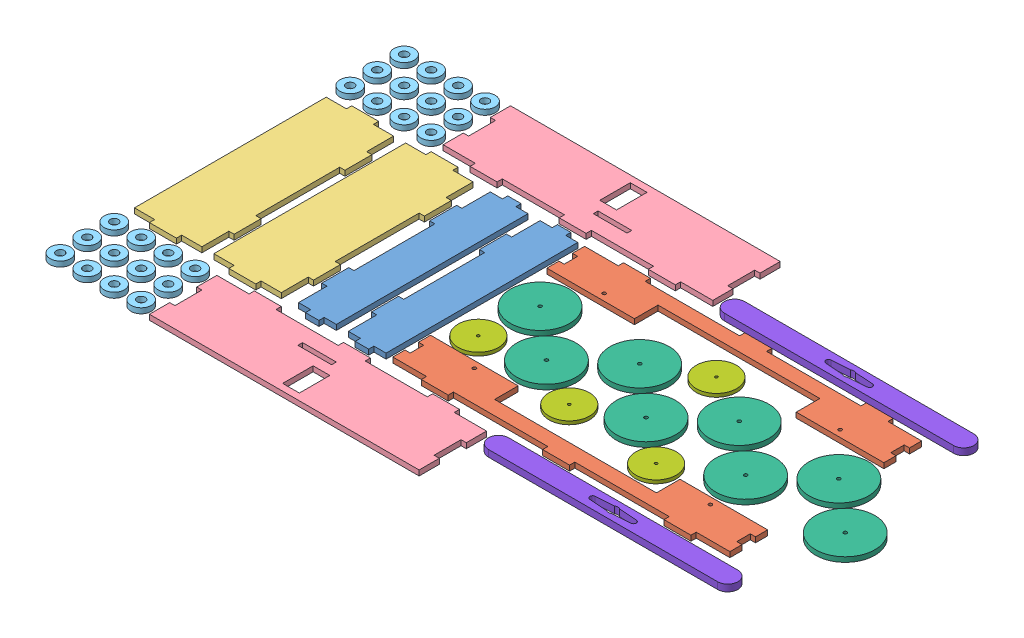
SolidWorks assembly Plastic Parts, configuration Default. Lengths in mm.
Overall size (510.29 5 275.55).
46 component instances, 8 part files, 135 mates.
Components (placement in the parent):
- Baseplate Short Side-1: Baseplate Short Side [Default] at (-426.9492 227.6568 258.8774) x (0 0 -1) z (1 0 0) size (150 3.9 31.9)
- Baseplate Wide Side-1: Baseplate Wide Side [Default] at (-246.0492 227.6568 201.7774) size (250 3.9 31.9)
- Chassis Short Side-1: Chassis Short Side [Default] at (-478.7492 227.6568 258.8774) x (0 0 -1) z (1 0 0) size (150 3.9 53.9)
- Chassis Wide Side-1: Chassis Wide Side [Default] at (-388.7492 227.6568 367.7774) size (200 3.9 53.9)
- Chassis Short Side-2: Chassis Short Side [Default] at (-537.6492 227.6568 258.8774) x (0 0 -1) z (1 0 0) size (150 3.9 53.9)
- Chassis Wide Side-2: Chassis Wide Side [Default] at (-388.7492 227.6568 149.9774) x (-1 0 0) z (0 0 -1) size (200 3.9 53.9)
- Baseplate Wide Side-2: Baseplate Wide Side [Default] at (-246.0492 227.6568 315.9774) x (-1 0 0) z (0 0 -1) size (250 3.9 31.9)
- Baseplate Short Side-2: Baseplate Short Side [Default] at (-390.0492 227.6568 258.8774) x (0 0 -1) z (1 0 0) size (150 3.9 31.9)
- Lift Axle-41: Lift Axle [Just the End] at (-561.2492 231.5568 346.3774) x (-0.413278 0 0.910605) z (0 -1 0) size (15 15 3.9)
- Lift Axle-42: Lift Axle [Just the End] at (-561.2492 231.5568 366.3774) x (-0.837224 0 -0.54686) z (0 -1 0) size (15 15 3.9)
- Lift Axle-43: Lift Axle [Just the End] at (-541.2492 231.5568 366.3774) x (-0.923391 0 -0.383861) z (0 -1 0) size (15 15 3.9)
- Lift Axle-44: Lift Axle [Just the End] at (-541.2492 231.5568 346.3774) x (0.712983 0 -0.701181) z (0 -1 0) size (15 15 3.9)
- Lift Axle-45: Lift Axle [Just the End] at (-521.2492 231.5568 346.3774) x (-0.688929 0 0.724829) z (0 -1 0) size (15 15 3.9)
- Lift Axle-46: Lift Axle [Just the End] at (-501.2492 231.5568 346.3774) x (-0.846423 0 -0.532511) z (0 -1 0) size (15 15 3.9)
- Lift Axle-47: Lift Axle [Just the End] at (-521.2492 231.5568 366.3774) x (-0.83717 0 -0.546942) z (0 -1 0) size (15 15 3.9)
- Lift Axle-48: Lift Axle [Just the End] at (-501.2492 231.5568 366.3774) x (-0.837169 0 -0.546945) z (0 -1 0) size (15 15 3.9)
- Wheel-1: Wheel [Just the End] at (-312.1147 285.9568 274.9774) x (0 1 0) z (0.574634 0 -0.818411) size (3.6 44 44)
- Wheel-2: Wheel [Just the End] at (-164.3766 285.9568 274.9774) x (0 1 0) z (0.049423 0 0.998778) size (3.6 44 44)
- Wheel-3: Wheel [Just the End] at (-90.5075 285.9568 274.9774) x (0 1 0) z (0.909173 0 -0.416419) size (3.6 44 44)
- Wheel-4: Wheel [Just the End] at (-238.2456 285.9568 274.9774) x (0 1 0) z (0.210384 0 0.977619) size (3.6 44 44)
- Pulley-1: Pulley [Just the End] at (-238.2456 241.5568 222.7814) x (0 1 0) z (-0.546944 0 0.837169) size (2.5 30 30)
- Pulley-3: Pulley [Just the End] at (-352.9996 241.5568 284.5912) x (0 1 0) z (0.807904 0 0.589315) size (2.5 30 30)
- Balance-1: Balance [Servo] at (-191.2492 226.5568 171.3774) size (185 5 15)
- Balance-2: Balance [Servo] at (-191.2492 226.5568 346.3774) size (185 5 15)
- Wheel-5: Wheel [Just the End] at (-201.3111 285.9568 242.7774) x (0 1 0) z (0.153769 0 0.988107) size (3.6 44 44)
- Wheel-6: Wheel [Just the End] at (-275.1802 285.9568 242.7774) x (0 1 0) z (0.291849 0 0.956464) size (3.6 44 44)
- Wheel-7: Wheel [Just the End] at (-127.442 285.9568 242.7774) x (0 1 0) z (-0.72689 0 0.686754) size (3.6 44 44)
- Wheel-8: Wheel [Just the End] at (-349.0492 285.9568 242.7774) x (0 1 0) z (-0.941015 0 0.338365) size (3.6 44 44)
- Lift Axle-57: Lift Axle [Just the End] at (-561.2492 231.5568 386.3774) x (0.928801 0 0.370578) z (0 -1 0) size (15 15 3.9)
- Lift Axle-58: Lift Axle [Just the End] at (-521.2492 231.5568 386.3774) x (-0.835695 0 -0.549193) z (0 -1 0) size (15 15 3.9)
- Lift Axle-59: Lift Axle [Just the End] at (-501.2492 231.5568 386.3774) x (0.447514 0 -0.894277) z (0 -1 0) size (15 15 3.9)
- Lift Axle-60: Lift Axle [Just the End] at (-541.2492 231.5568 386.3774) x (-0.998692 0 -0.051123) z (0 -1 0) size (15 15 3.9)
- Pulley-5: Pulley [Just the End] at (-205.0492 241.5568 300.7068) x (0 1 0) z (-0.924047 0 -0.382279) size (2.5 30 30)
- Pulley-6: Pulley [Just the End] at (-275.1802 241.5568 294.9734) x (0 1 0) z (0.752429 0 -0.658674) size (2.5 30 30)
- Lift Axle-66: Lift Axle [Just the End] at (-521.2492 231.5568 171.3774) x (-0.999114 0 -0.042077) z (0 -1 0) size (15 15 3.9)
- Lift Axle-67: Lift Axle [Just the End] at (-561.2492 231.5568 171.3774) x (0.447514 0 -0.894277) z (0 -1 0) size (15 15 3.9)
- Lift Axle-68: Lift Axle [Just the End] at (-541.2492 231.5568 171.3774) x (-0.879242 0 -0.476376) z (0 -1 0) size (15 15 3.9)
- Lift Axle-69: Lift Axle [Just the End] at (-501.2492 231.5568 171.3774) x (0.91604 0 0.401086) z (0 -1 0) size (15 15 3.9)
- Lift Axle-70: Lift Axle [Just the End] at (-521.2492 231.5568 151.3774) x (-0.879242 0 -0.476376) z (0 -1 0) size (15 15 3.9)
- Lift Axle-71: Lift Axle [Just the End] at (-541.2492 231.5568 151.3774) x (-0.998932 0 -0.046213) z (0 -1 0) size (15 15 3.9)
- Lift Axle-72: Lift Axle [Just the End] at (-501.2492 231.5568 151.3774) x (0.448674 0 -0.893696) z (0 -1 0) size (15 15 3.9)
- Lift Axle-73: Lift Axle [Just the End] at (-561.2492 231.5568 151.3774) x (0.91604 0 0.401086) z (0 -1 0) size (15 15 3.9)
- Lift Axle-74: Lift Axle [Just the End] at (-541.2492 231.5568 131.3774) x (-0.879242 0 -0.476376) z (0 -1 0) size (15 15 3.9)
- Lift Axle-75: Lift Axle [Just the End] at (-521.2492 231.5568 131.3774) x (-0.999822 0 -0.018854) z (0 -1 0) size (15 15 3.9)
- Lift Axle-76: Lift Axle [Just the End] at (-561.2492 231.5568 131.3774) x (0.447514 0 -0.894277) z (0 -1 0) size (15 15 3.9)
- Lift Axle-77: Lift Axle [Just the End] at (-501.2492 231.5568 131.3774) x (0.359916 0 0.932985) z (0 -1 0) size (15 15 3.9)
Mates (geometry in assembly coordinates):
- Coincident2: coincident aligned: plane of Baseplate Wide Side-1 through (-246.0492 231.5568 201.7774) normal (0 1 0); plane of Chassis Short Side-1 through (-478.7492 231.5568 258.8774) normal (0 1 0)
- Coincident3: coincident aligned: plane of Baseplate Wide Side-1 through (-246.0492 231.5568 201.7774) normal (0 1 0); plane of Chassis Wide Side-1 through (-388.7492 231.5568 367.7774) normal (0 1 0)
- Coincident5: coincident aligned: plane of Baseplate Short Side-1 through (-426.9492 231.5568 258.8774) normal (0 1 0); plane of Baseplate Wide Side-1 through (-246.0492 231.5568 201.7774) normal (0 1 0)
- Coincident17: coincident aligned: plane of Chassis Short Side-1 through (-478.7492 231.5568 258.8774) normal (0 1 0); plane of Chassis Short Side-2 through (-537.6492 231.5568 258.8774) normal (0 1 0)
- Coincident18: coincident aligned: plane of Chassis Short Side-1 through (-488.7492 231.5568 183.8774) normal (0 0 -1); plane of Chassis Short Side-2 through (-547.6492 231.5568 183.8774) normal (0 0 -1)
- Distance7: distance = 5 mm anti-aligned: plane of Chassis Short Side-2 through (-508.7492 231.5568 227.7774) normal (1 0 0); plane of Chassis Short Side-1 through (-503.7492 231.5568 329.9774) normal (-1 0 0)
- Distance11: distance = 5 mm anti-aligned: plane of Baseplate Short Side-1 through (-412.9492 231.5568 329.9774) normal (1 0 0); plane of Baseplate Short Side-2 through (-407.9492 231.5568 208.8774) normal (-1 0 0)
- Coincident33: coincident aligned: plane of Baseplate Short Side-1 through (-426.9492 231.5568 258.8774) normal (0 1 0); plane of Baseplate Short Side-2 through (-390.0492 231.5568 258.8774) normal (0 1 0)
- Coincident34: coincident aligned: plane of Baseplate Short Side-1 through (-431.9492 231.5568 183.8774) normal (0 0 -1); plane of Baseplate Short Side-2 through (-395.0492 231.5568 183.8774) normal (0 0 -1)
- Coincident69: coincident aligned: plane of Lift Axle-45 through (-521.2492 231.5568 346.3774) normal (0 1 0); plane of Lift Axle-48 through (-501.2492 231.5568 366.3774) normal (0 1 0)
- Coincident70: coincident aligned: plane of Lift Axle-45 through (-521.2492 231.5568 346.3774) normal (0 1 0); plane of Lift Axle-46 through (-501.2492 231.5568 346.3774) normal (0 1 0)
- Coincident71: coincident aligned: plane of Lift Axle-44 through (-541.2492 231.5568 346.3774) normal (0 1 0); plane of Lift Axle-45 through (-521.2492 231.5568 346.3774) normal (0 1 0)
- Coincident72: coincident aligned: plane of Lift Axle-42 through (-561.2492 231.5568 366.3774) normal (0 1 0); plane of Lift Axle-45 through (-521.2492 231.5568 346.3774) normal (0 1 0)
- Coincident73: coincident aligned: plane of Lift Axle-43 through (-541.2492 231.5568 366.3774) normal (0 1 0); plane of Lift Axle-45 through (-521.2492 231.5568 346.3774) normal (0 1 0)
- Coincident74: coincident aligned: plane of Lift Axle-45 through (-521.2492 231.5568 346.3774) normal (0 1 0); plane of Lift Axle-47 through (-521.2492 231.5568 366.3774) normal (0 1 0)
- Coincident75: coincident aligned: plane of Lift Axle-41 through (-561.2492 231.5568 346.3774) normal (0 1 0); plane of Lift Axle-45 through (-521.2492 231.5568 346.3774) normal (0 1 0)
- Distance87: distance = 5 mm: cylinder of Lift Axle-43 through (-541.2492 227.6568 366.3774) axis (0 1 0) radius 7.5; cylinder of Lift Axle-47 through (-521.2492 227.6568 366.3774) axis (0 1 0) radius 7.5
- Distance88: distance = 5 mm: cylinder of Lift Axle-47 through (-521.2492 227.6568 366.3774) axis (0 1 0) radius 7.5; cylinder of Lift Axle-48 through (-501.2492 227.6568 366.3774) axis (0 1 0) radius 7.5
- Distance89: distance = 5 mm: cylinder of Lift Axle-46 through (-501.2492 227.6568 346.3774) axis (0 1 0) radius 7.5; cylinder of Lift Axle-48 through (-501.2492 227.6568 366.3774) axis (0 1 0) radius 7.5
- Distance90: distance = 5 mm: cylinder of Lift Axle-44 through (-541.2492 227.6568 346.3774) axis (0 1 0) radius 7.5; cylinder of Lift Axle-41 through (-561.2492 227.6568 346.3774) axis (0 1 0) radius 7.5
- Distance91: distance = 5 mm: cylinder of Lift Axle-45 through (-521.2492 227.6568 346.3774) axis (0 1 0) radius 7.5; cylinder of Lift Axle-44 through (-541.2492 227.6568 346.3774) axis (0 1 0) radius 7.5
- Distance92: distance = 5 mm: cylinder of Lift Axle-42 through (-561.2492 227.6568 366.3774) axis (0 1 0) radius 7.5; cylinder of Lift Axle-43 through (-541.2492 227.6568 366.3774) axis (0 1 0) radius 7.5
- Distance93: distance = 5 mm: cylinder of Lift Axle-45 through (-521.2492 227.6568 346.3774) axis (0 1 0) radius 7.5; cylinder of Lift Axle-47 through (-521.2492 227.6568 366.3774) axis (0 1 0) radius 7.5
- Distance94: distance = 5 mm: cylinder of Lift Axle-44 through (-541.2492 227.6568 346.3774) axis (0 1 0) radius 7.5; cylinder of Lift Axle-43 through (-541.2492 227.6568 366.3774) axis (0 1 0) radius 7.5
- Distance95: distance = 5 mm: cylinder of Lift Axle-41 through (-561.2492 227.6568 346.3774) axis (0 1 0) radius 7.5; cylinder of Lift Axle-42 through (-561.2492 227.6568 366.3774) axis (0 1 0) radius 7.5
- Distance96: distance = 5 mm: cylinder of Lift Axle-46 through (-501.2492 227.6568 346.3774) axis (0 1 0) radius 7.5; cylinder of Lift Axle-45 through (-521.2492 227.6568 346.3774) axis (0 1 0) radius 7.5
- Coincident76: coincident aligned: plane of Chassis Wide Side-1 through (-388.7492 231.5568 367.7774) normal (0 1 0); plane of Lift Axle-46 through (-501.2492 231.5568 346.3774) normal (0 1 0)
- Distance97: distance = 5 mm anti-aligned: cylinder of Lift Axle-46 through (-501.2492 227.6568 346.3774) axis (0 1 0) radius 7.5; plane of Chassis Short Side-1 through (-488.7492 231.5568 333.8774) normal (0 0 1)
- Distance98: distance = 5 mm anti-aligned: cylinder of Lift Axle-46 through (-501.2492 227.6568 346.3774) axis (0 1 0) radius 7.5; plane of Chassis Wide Side-1 through (-488.7492 231.5568 367.7774) normal (-1 0 0)
- Distance99: distance = 5 mm anti-aligned: cylinder of Lift Axle-48 through (-501.2492 227.6568 366.3774) axis (0 1 0) radius 7.5; plane of Chassis Wide Side-1 through (-488.7492 231.5568 367.7774) normal (-1 0 0)
- Distance100: distance = 5 mm anti-aligned: cylinder of Lift Axle-45 through (-521.2492 227.6568 346.3774) axis (0 1 0) radius 7.5; plane of Chassis Short Side-1 through (-488.7492 231.5568 333.8774) normal (0 0 1)
- Distance101: distance = 5 mm anti-aligned: cylinder of Lift Axle-44 through (-541.2492 227.6568 346.3774) axis (0 1 0) radius 7.5; plane of Chassis Short Side-1 through (-488.7492 231.5568 333.8774) normal (0 0 1)
- Distance102: distance = 5 mm anti-aligned: cylinder of Lift Axle-41 through (-561.2492 227.6568 346.3774) axis (0 1 0) radius 7.5; plane of Chassis Short Side-2 through (-547.6492 231.5568 333.8774) normal (0 0 1)
- Coincident86: coincident aligned: plane of Wheel-3 through (-90.5075 231.5568 274.9774) normal (0 1 0); plane of Wheel-4 through (-238.2456 231.5568 274.9774) normal (0 1 0)
- Coincident87: coincident aligned: plane of Wheel-2 through (-164.3766 231.5568 274.9774) normal (0 1 0); plane of Wheel-4 through (-238.2456 231.5568 274.9774) normal (0 1 0)
- Coincident88: coincident aligned: plane of Wheel-1 through (-312.1147 231.5568 274.9774) normal (0 1 0); plane of Wheel-4 through (-238.2456 231.5568 274.9774) normal (0 1 0)
- Coincident89: coincident aligned: plane of Baseplate Wide Side-2 through (-246.0492 231.5568 315.9774) normal (0 1 0); plane of Wheel-4 through (-238.2456 231.5568 274.9774) normal (0 1 0)
- Distance124: distance = 5 mm anti-aligned: cylinder of Wheel-3 through (-90.5075 285.9568 274.9774) axis (0 1 0) radius 22; plane of Baseplate Wide Side-2 through (-246.0492 231.5568 301.9774) normal (0 0 -1)
- Distance126: distance = 5 mm anti-aligned: cylinder of Wheel-4 through (-238.2456 285.9568 274.9774) axis (0 1 0) radius 22; plane of Baseplate Wide Side-2 through (-246.0492 231.5568 301.9774) normal (0 0 -1)
- Distance128: distance = 5 mm anti-aligned: cylinder of Wheel-2 through (-164.3766 285.9568 274.9774) axis (0 1 0) radius 22; plane of Baseplate Wide Side-2 through (-246.0492 231.5568 301.9774) normal (0 0 -1)
- Coincident100: coincident aligned: plane of Baseplate Wide Side-2 through (-246.0492 231.5568 315.9774) normal (0 1 0); plane of Pulley-1 through (-238.2456 231.5568 222.7814) normal (0 1 0)
- Coincident101: coincident aligned: plane of Baseplate Short Side-2 through (-390.0492 231.5568 258.8774) normal (0 1 0); plane of Pulley-3 through (-352.9996 231.5568 284.5912) normal (0 1 0)
- Coincident102: coincident: plane of Chassis Wide Side-1 through (-388.7492 231.5568 367.7774) normal (0 1 0); plane of Balance-2 through (-196.6235 231.5568 346.3774) normal (0 1 0)
- Coincident103: coincident aligned: plane of Wheel-5 through (-201.3111 231.5568 242.7774) normal (0 1 0); plane of Wheel-7 through (-127.442 231.5568 242.7774) normal (0 1 0)
- Coincident104: coincident aligned: plane of Wheel-5 through (-201.3111 231.5568 242.7774) normal (0 1 0); plane of Wheel-8 through (-349.0492 231.5568 242.7774) normal (0 1 0)
- Coincident105: coincident aligned: plane of Wheel-5 through (-201.3111 231.5568 242.7774) normal (0 1 0); plane of Wheel-6 through (-275.1802 231.5568 242.7774) normal (0 1 0)
- Distance142: distance = 5 mm anti-aligned: cylinder of Wheel-7 through (-127.442 285.9568 242.7774) axis (0 1 0) radius 22; plane of Baseplate Wide Side-1 through (-246.0492 231.5568 215.7774) normal (0 0 1)
- Distance143: distance = 5 mm anti-aligned: cylinder of Wheel-5 through (-201.3111 285.9568 242.7774) axis (0 1 0) radius 22; plane of Baseplate Wide Side-1 through (-246.0492 231.5568 215.7774) normal (0 0 1)
- Distance144: distance = 5 mm anti-aligned: cylinder of Wheel-6 through (-275.1802 285.9568 242.7774) axis (0 1 0) radius 22; plane of Baseplate Wide Side-1 through (-246.0492 231.5568 215.7774) normal (0 0 1)
- Distance145: distance = 5 mm anti-aligned: cylinder of Wheel-8 through (-349.0492 285.9568 242.7774) axis (0 1 0) radius 22; plane of Baseplate Wide Side-1 through (-246.0492 231.5568 215.7774) normal (0 0 1)
- Distance147: distance = 5 mm: cylinder of Lift Axle-60 through (-541.2492 227.6568 386.3774) axis (0 1 0) radius 7.5; cylinder of Lift Axle-58 through (-521.2492 227.6568 386.3774) axis (0 1 0) radius 7.5
- Distance148: distance = 5 mm: cylinder of Lift Axle-57 through (-561.2492 227.6568 386.3774) axis (0 1 0) radius 7.5; cylinder of Lift Axle-60 through (-541.2492 227.6568 386.3774) axis (0 1 0) radius 7.5
- Distance149: distance = 5 mm: cylinder of Lift Axle-58 through (-521.2492 227.6568 386.3774) axis (0 1 0) radius 7.5; cylinder of Lift Axle-59 through (-501.2492 227.6568 386.3774) axis (0 1 0) radius 7.5
- Distance150: distance = 5 mm: cylinder of Lift Axle-59 through (-501.2492 227.6568 386.3774) axis (0 1 0) radius 7.5; cylinder of Lift Axle-48 through (-501.2492 227.6568 366.3774) axis (0 1 0) radius 7.5
- Coincident113: coincident aligned: plane of Chassis Wide Side-1 through (-388.7492 231.5568 367.7774) normal (0 1 0); plane of Lift Axle-59 through (-501.2492 231.5568 386.3774) normal (0 1 0)
- Coincident114: coincident aligned: plane of Chassis Wide Side-1 through (-388.7492 231.5568 367.7774) normal (0 1 0); plane of Lift Axle-58 through (-521.2492 231.5568 386.3774) normal (0 1 0)
- Coincident115: coincident aligned: plane of Chassis Short Side-2 through (-537.6492 231.5568 258.8774) normal (0 1 0); plane of Lift Axle-57 through (-561.2492 231.5568 386.3774) normal (0 1 0)
- Coincident116: coincident aligned: plane of Chassis Short Side-1 through (-478.7492 231.5568 258.8774) normal (0 1 0); plane of Lift Axle-60 through (-541.2492 231.5568 386.3774) normal (0 1 0)
- Distance151: distance = 5 mm anti-aligned: cylinder of Lift Axle-59 through (-501.2492 227.6568 386.3774) axis (0 1 0) radius 7.5; plane of Chassis Wide Side-1 through (-488.7492 231.5568 367.7774) normal (-1 0 0)
- Distance153: distance = 5 mm: cylinder of Lift Axle-58 through (-521.2492 227.6568 386.3774) axis (0 1 0) radius 7.5; cylinder of Lift Axle-47 through (-521.2492 227.6568 366.3774) axis (0 1 0) radius 7.5
- Distance154: distance = 5 mm: cylinder of Lift Axle-60 through (-541.2492 227.6568 386.3774) axis (0 1 0) radius 7.5; cylinder of Lift Axle-43 through (-541.2492 227.6568 366.3774) axis (0 1 0) radius 7.5
- Distance156: distance = 5 mm: cylinder of Lift Axle-57 through (-561.2492 227.6568 386.3774) axis (0 1 0) radius 7.5; cylinder of Lift Axle-42 through (-561.2492 227.6568 366.3774) axis (0 1 0) radius 7.5
- Coincident128: coincident aligned: plane of Baseplate Short Side-1 through (-426.9492 231.5568 258.8774) normal (0 1 0); plane of Pulley-6 through (-275.1802 231.5568 294.9734) normal (0 1 0)
- Coincident129: coincident aligned: plane of Baseplate Short Side-2 through (-390.0492 231.5568 258.8774) normal (0 1 0); plane of Pulley-5 through (-205.0492 231.5568 300.7068) normal (0 1 0)
- Distance172: distance = 5 mm anti-aligned: plane of Baseplate Short Side-1 through (-444.8492 231.5568 208.8774) normal (-1 0 0); plane of Chassis Short Side-1 through (-449.8492 231.5568 227.7774) normal (1 0 0)
- Distance173: distance = 5 mm anti-aligned: plane of Baseplate Short Side-2 through (-395.0492 231.5568 333.8774) normal (0 0 1); plane of Chassis Wide Side-1 through (-388.7492 231.5568 338.8774) normal (0 0 -1)
- Coincident134: coincident aligned: plane of Chassis Wide Side-2 through (-388.7492 231.5568 149.9774) normal (0 1 0); plane of Baseplate Short Side-2 through (-390.0492 231.5568 258.8774) normal (0 1 0)
- Coincident135: coincident aligned: plane of Chassis Wide Side-1 through (-388.7492 231.5568 367.7774) normal (0 1 0); plane of Baseplate Wide Side-2 through (-246.0492 231.5568 315.9774) normal (0 1 0)
- Distance174: distance = 5 mm anti-aligned: plane of Baseplate Wide Side-2 through (-371.0492 231.5568 315.9774) normal (-1 0 0); plane of Baseplate Short Side-2 through (-376.0492 231.5568 329.9774) normal (1 0 0)
- Distance176: distance = 5 mm anti-aligned: plane of Chassis Wide Side-1 through (-388.7492 231.5568 338.8774) normal (0 0 -1); plane of Baseplate Wide Side-2 through (-246.0492 231.5568 333.8774) normal (0 0 1)
- Distance177: distance = 5 mm anti-aligned: plane of Baseplate Short Side-2 through (-395.0492 231.5568 183.8774) normal (0 0 -1); plane of Chassis Wide Side-2 through (-388.7492 231.5568 178.8774) normal (0 0 1)
- Coincident146: coincident aligned: plane of Chassis Short Side-1 through (-488.7492 231.5568 187.7774) normal (-1 0 0); plane of Chassis Wide Side-2 through (-488.7492 231.5568 149.9774) normal (-1 0 0)
- Coincident147: coincident aligned: plane of Chassis Short Side-1 through (-488.7492 231.5568 329.9774) normal (-1 0 0); plane of Chassis Wide Side-1 through (-488.7492 231.5568 367.7774) normal (-1 0 0)
- Distance178: distance = 5 mm anti-aligned: plane of Chassis Short Side-1 through (-488.7492 231.5568 183.8774) normal (0 0 -1); plane of Chassis Wide Side-2 through (-388.7492 231.5568 178.8774) normal (0 0 1)
- Coincident149: coincident aligned: plane of Chassis Wide Side-2 through (-388.7492 231.5568 149.9774) normal (0 1 0); plane of Balance-1 through (-191.2492 231.5568 171.3774) normal (0 1 0)
- Coincident152: coincident aligned: plane of Chassis Wide Side-2 through (-388.7492 231.5568 149.9774) normal (0 1 0); plane of Wheel-8 through (-349.0492 231.5568 242.7774) normal (0 1 0)
- Distance185: distance = 5 mm anti-aligned: plane of Baseplate Wide Side-1 through (-246.0492 231.5568 183.8774) normal (0 0 -1); plane of Chassis Wide Side-2 through (-388.7492 231.5568 178.8774) normal (0 0 1)
- Distance186: distance = 5 mm anti-aligned: plane of Baseplate Short Side-2 through (-376.0492 231.5568 329.9774) normal (1 0 0); plane of Baseplate Wide Side-1 through (-371.0492 231.5568 201.7774) normal (-1 0 0)
- Distance187: distance = 5 mm anti-aligned: cylinder of Wheel-1 through (-312.1147 285.9568 274.9774) axis (0 1 0) radius 22; plane of Baseplate Wide Side-2 through (-246.0492 231.5568 301.9774) normal (0 0 -1)
- Distance188: distance = 5 mm: cylinder of Wheel-1 through (-312.1147 285.9568 274.9774) axis (0 1 0) radius 22; cylinder of Wheel-8 through (-349.0492 285.9568 242.7774) axis (0 1 0) radius 22
- Distance189: distance = 5 mm anti-aligned: plane of Baseplate Short Side-2 through (-376.0492 231.5568 329.9774) normal (1 0 0); cylinder of Wheel-8 through (-349.0492 285.9568 242.7774) axis (0 1 0) radius 22
- Distance190: distance = 5 mm: cylinder of Wheel-6 through (-275.1802 285.9568 242.7774) axis (0 1 0) radius 22; cylinder of Wheel-1 through (-312.1147 285.9568 274.9774) axis (0 1 0) radius 22
- Distance191: distance = 5 mm: cylinder of Wheel-4 through (-238.2456 285.9568 274.9774) axis (0 1 0) radius 22; cylinder of Wheel-6 through (-275.1802 285.9568 242.7774) axis (0 1 0) radius 22
- Distance192: distance = 5 mm: cylinder of Wheel-5 through (-201.3111 285.9568 242.7774) axis (0 1 0) radius 22; cylinder of Wheel-4 through (-238.2456 285.9568 274.9774) axis (0 1 0) radius 22
- Distance193: distance = 5 mm: cylinder of Wheel-2 through (-164.3766 285.9568 274.9774) axis (0 1 0) radius 22; cylinder of Wheel-5 through (-201.3111 285.9568 242.7774) axis (0 1 0) radius 22
- Distance194: distance = 5 mm: cylinder of Wheel-7 through (-127.442 285.9568 242.7774) axis (0 1 0) radius 22; cylinder of Wheel-2 through (-164.3766 285.9568 274.9774) axis (0 1 0) radius 22
- Distance195: distance = 5 mm: cylinder of Wheel-3 through (-90.5075 285.9568 274.9774) axis (0 1 0) radius 22; cylinder of Wheel-7 through (-127.442 285.9568 242.7774) axis (0 1 0) radius 22
- Distance196: distance = 5 mm: cylinder of Wheel-4 through (-238.2456 285.9568 274.9774) axis (0 1 0) radius 22; cylinder of Pulley-6 through (-275.1802 229.0568 294.9734) axis (0 -1 0) radius 15
- Distance197: distance = 5 mm: cylinder of Pulley-6 through (-275.1802 229.0568 294.9734) axis (0 -1 0) radius 15; cylinder of Wheel-1 through (-312.1147 285.9568 274.9774) axis (0 1 0) radius 22
- Distance199: distance = 5 mm: cylinder of Wheel-4 through (-238.2456 285.9568 274.9774) axis (0 1 0) radius 22; cylinder of Pulley-5 through (-205.0492 229.0568 300.7068) axis (0 -1 0) radius 15
- Distance201: distance = 5 mm: cylinder of Wheel-1 through (-312.1147 285.9568 274.9774) axis (0 1 0) radius 22; cylinder of Pulley-3 through (-352.9996 229.0568 284.5912) axis (0 -1 0) radius 15
- Distance202: distance = 5 mm: cylinder of Pulley-3 through (-352.9996 229.0568 284.5912) axis (0 -1 0) radius 15; cylinder of Wheel-8 through (-349.0492 285.9568 242.7774) axis (0 1 0) radius 22
- Distance203: distance = 5 mm: cylinder of Pulley-1 through (-238.2456 229.0568 222.7814) axis (0 -1 0) radius 15; cylinder of Wheel-5 through (-201.3111 285.9568 242.7774) axis (0 1 0) radius 22
- Distance204: distance = 5 mm: cylinder of Pulley-1 through (-238.2456 229.0568 222.7814) axis (0 -1 0) radius 15; cylinder of Wheel-6 through (-275.1802 285.9568 242.7774) axis (0 1 0) radius 22
- Distance205: distance = 4 mm anti-aligned: plane of Baseplate Wide Side-2 through (-186.0492 231.5568 315.9774) normal (-1 0 0); cylinder of Pulley-5 through (-205.0492 229.0568 300.7068) axis (0 -1 0) radius 15
- Distance206: distance = 5 mm: cylinder of Lift Axle-68 through (-541.2492 227.6568 171.3774) axis (0 1 0) radius 7.5; cylinder of Lift Axle-67 through (-561.2492 227.6568 171.3774) axis (0 1 0) radius 7.5
- Distance207: distance = 5 mm: cylinder of Lift Axle-66 through (-521.2492 227.6568 171.3774) axis (0 1 0) radius 7.5; cylinder of Lift Axle-68 through (-541.2492 227.6568 171.3774) axis (0 1 0) radius 7.5
- Distance208: distance = 5 mm: cylinder of Lift Axle-69 through (-501.2492 227.6568 171.3774) axis (0 1 0) radius 7.5; cylinder of Lift Axle-66 through (-521.2492 227.6568 171.3774) axis (0 1 0) radius 7.5
- Coincident157: coincident aligned: plane of Chassis Short Side-2 through (-537.6492 231.5568 258.8774) normal (0 1 0); plane of Lift Axle-67 through (-561.2492 231.5568 171.3774) normal (0 1 0)
- Coincident158: coincident aligned: plane of Chassis Short Side-2 through (-537.6492 231.5568 258.8774) normal (0 1 0); plane of Lift Axle-69 through (-501.2492 231.5568 171.3774) normal (0 1 0)
- Coincident159: coincident aligned: plane of Chassis Short Side-2 through (-537.6492 231.5568 258.8774) normal (0 1 0); plane of Lift Axle-68 through (-541.2492 231.5568 171.3774) normal (0 1 0)
- Coincident160: coincident aligned: plane of Chassis Short Side-2 through (-537.6492 231.5568 258.8774) normal (0 1 0); plane of Lift Axle-66 through (-521.2492 231.5568 171.3774) normal (0 1 0)
- Distance209: distance = 5 mm anti-aligned: cylinder of Lift Axle-69 through (-501.2492 227.6568 171.3774) axis (0 1 0) radius 7.5; plane of Chassis Short Side-2 through (-547.6492 231.5568 183.8774) normal (0 0 -1)
- Distance210: distance = 5 mm anti-aligned: cylinder of Lift Axle-66 through (-521.2492 227.6568 171.3774) axis (0 1 0) radius 7.5; plane of Chassis Short Side-2 through (-547.6492 231.5568 183.8774) normal (0 0 -1)
- Distance211: distance = 5 mm anti-aligned: cylinder of Lift Axle-68 through (-541.2492 227.6568 171.3774) axis (0 1 0) radius 7.5; plane of Chassis Short Side-2 through (-547.6492 231.5568 183.8774) normal (0 0 -1)
- Distance212: distance = 5 mm anti-aligned: cylinder of Lift Axle-67 through (-561.2492 227.6568 171.3774) axis (0 1 0) radius 7.5; plane of Chassis Short Side-2 through (-547.6492 231.5568 183.8774) normal (0 0 -1)
- Distance213: distance = 5 mm anti-aligned: cylinder of Lift Axle-69 through (-501.2492 227.6568 171.3774) axis (0 1 0) radius 7.5; plane of Chassis Wide Side-2 through (-488.7492 231.5568 149.9774) normal (-1 0 0)
- Distance214: distance = 5 mm: cylinder of Lift Axle-73 through (-561.2492 227.6568 151.3774) axis (0 1 0) radius 7.5; cylinder of Lift Axle-71 through (-541.2492 227.6568 151.3774) axis (0 1 0) radius 7.5
- Distance215: distance = 5 mm: cylinder of Lift Axle-71 through (-541.2492 227.6568 151.3774) axis (0 1 0) radius 7.5; cylinder of Lift Axle-70 through (-521.2492 227.6568 151.3774) axis (0 1 0) radius 7.5
- Distance216: distance = 5 mm: cylinder of Lift Axle-70 through (-521.2492 227.6568 151.3774) axis (0 1 0) radius 7.5; cylinder of Lift Axle-72 through (-501.2492 227.6568 151.3774) axis (0 1 0) radius 7.5
- Distance217: distance = 5 mm: cylinder of Lift Axle-77 through (-501.2492 227.6568 131.3774) axis (0 1 0) radius 7.5; cylinder of Lift Axle-75 through (-521.2492 227.6568 131.3774) axis (0 1 0) radius 7.5
- Distance218: distance = 5 mm: cylinder of Lift Axle-75 through (-521.2492 227.6568 131.3774) axis (0 1 0) radius 7.5; cylinder of Lift Axle-74 through (-541.2492 227.6568 131.3774) axis (0 1 0) radius 7.5
- Distance219: distance = 5 mm: cylinder of Lift Axle-74 through (-541.2492 227.6568 131.3774) axis (0 1 0) radius 7.5; cylinder of Lift Axle-76 through (-561.2492 227.6568 131.3774) axis (0 1 0) radius 7.5
- Coincident161: coincident aligned: plane of Chassis Wide Side-2 through (-388.7492 231.5568 149.9774) normal (0 1 0); plane of Lift Axle-73 through (-561.2492 231.5568 151.3774) normal (0 1 0)
- Coincident162: coincident aligned: plane of Chassis Wide Side-2 through (-388.7492 231.5568 149.9774) normal (0 1 0); plane of Lift Axle-71 through (-541.2492 231.5568 151.3774) normal (0 1 0)
- Coincident163: coincident aligned: plane of Chassis Wide Side-2 through (-388.7492 231.5568 149.9774) normal (0 1 0); plane of Lift Axle-70 through (-521.2492 231.5568 151.3774) normal (0 1 0)
- Coincident164: coincident aligned: plane of Chassis Wide Side-2 through (-388.7492 231.5568 149.9774) normal (0 1 0); plane of Lift Axle-72 through (-501.2492 231.5568 151.3774) normal (0 1 0)
- Coincident165: coincident aligned: plane of Chassis Wide Side-2 through (-388.7492 231.5568 149.9774) normal (0 1 0); plane of Lift Axle-76 through (-561.2492 231.5568 131.3774) normal (0 1 0)
- Coincident166: coincident aligned: plane of Chassis Wide Side-2 through (-388.7492 231.5568 149.9774) normal (0 1 0); plane of Lift Axle-74 through (-541.2492 231.5568 131.3774) normal (0 1 0)
- Coincident167: coincident aligned: plane of Chassis Wide Side-2 through (-388.7492 231.5568 149.9774) normal (0 1 0); plane of Lift Axle-75 through (-521.2492 231.5568 131.3774) normal (0 1 0)
- Coincident168: coincident aligned: plane of Chassis Wide Side-2 through (-388.7492 231.5568 149.9774) normal (0 1 0); plane of Lift Axle-77 through (-501.2492 231.5568 131.3774) normal (0 1 0)
- Distance220: distance = 5 mm anti-aligned: cylinder of Lift Axle-72 through (-501.2492 227.6568 151.3774) axis (0 1 0) radius 7.5; plane of Chassis Wide Side-2 through (-488.7492 231.5568 149.9774) normal (-1 0 0)
- Distance221: distance = 5 mm anti-aligned: cylinder of Lift Axle-77 through (-501.2492 227.6568 131.3774) axis (0 1 0) radius 7.5; plane of Chassis Wide Side-2 through (-488.7492 231.5568 149.9774) normal (-1 0 0)
- Distance223: distance = 5 mm: cylinder of Lift Axle-72 through (-501.2492 227.6568 151.3774) axis (0 1 0) radius 7.5; cylinder of Lift Axle-69 through (-501.2492 227.6568 171.3774) axis (0 1 0) radius 7.5
- Distance224: distance = 5 mm: cylinder of Lift Axle-70 through (-521.2492 227.6568 151.3774) axis (0 1 0) radius 7.5; cylinder of Lift Axle-66 through (-521.2492 227.6568 171.3774) axis (0 1 0) radius 7.5
- Distance225: distance = 5 mm: cylinder of Lift Axle-71 through (-541.2492 227.6568 151.3774) axis (0 1 0) radius 7.5; cylinder of Lift Axle-68 through (-541.2492 227.6568 171.3774) axis (0 1 0) radius 7.5
- Distance226: distance = 5 mm: cylinder of Lift Axle-73 through (-561.2492 227.6568 151.3774) axis (0 1 0) radius 7.5; cylinder of Lift Axle-67 through (-561.2492 227.6568 171.3774) axis (0 1 0) radius 7.5
- Distance227: distance = 5 mm: cylinder of Lift Axle-77 through (-501.2492 227.6568 131.3774) axis (0 1 0) radius 7.5; cylinder of Lift Axle-72 through (-501.2492 227.6568 151.3774) axis (0 1 0) radius 7.5
- Distance228: distance = 5 mm: cylinder of Lift Axle-75 through (-521.2492 227.6568 131.3774) axis (0 1 0) radius 7.5; cylinder of Lift Axle-70 through (-521.2492 227.6568 151.3774) axis (0 1 0) radius 7.5
- Distance229: distance = 5 mm: cylinder of Lift Axle-74 through (-541.2492 227.6568 131.3774) axis (0 1 0) radius 7.5; cylinder of Lift Axle-71 through (-541.2492 227.6568 151.3774) axis (0 1 0) radius 7.5
- Distance230: distance = 5 mm: cylinder of Lift Axle-76 through (-561.2492 227.6568 131.3774) axis (0 1 0) radius 7.5; cylinder of Lift Axle-73 through (-561.2492 227.6568 151.3774) axis (0 1 0) radius 7.5
- Distance231: distance = 5 mm anti-aligned: cylinder of Balance-1 through (-276.2492 231.5568 171.3774) axis (0 -1 0) radius 7.5; plane of Chassis Wide Side-2 through (-288.7492 231.5568 149.9774) normal (1 0 0)
- Distance232: distance = 5 mm anti-aligned: plane of Balance-1 through (-191.2492 231.5568 178.8774) normal (0 0 1); plane of Baseplate Wide Side-1 through (-246.0492 231.5568 183.8774) normal (0 0 -1)
- Distance233: distance = 5 mm: plane of Baseplate Wide Side-2 through (-246.0492 231.5568 333.8774) normal (0 0 1); plane of Balance-2 through (-191.2492 231.5568 338.8774) normal (0 0 -1)
- Distance234: distance = 5 mm anti-aligned: plane of Chassis Wide Side-1 through (-288.7492 231.5568 367.7774) normal (1 0 0); cylinder of Balance-2 through (-276.2492 231.5568 346.3774) axis (0 -1 0) radius 7.5
